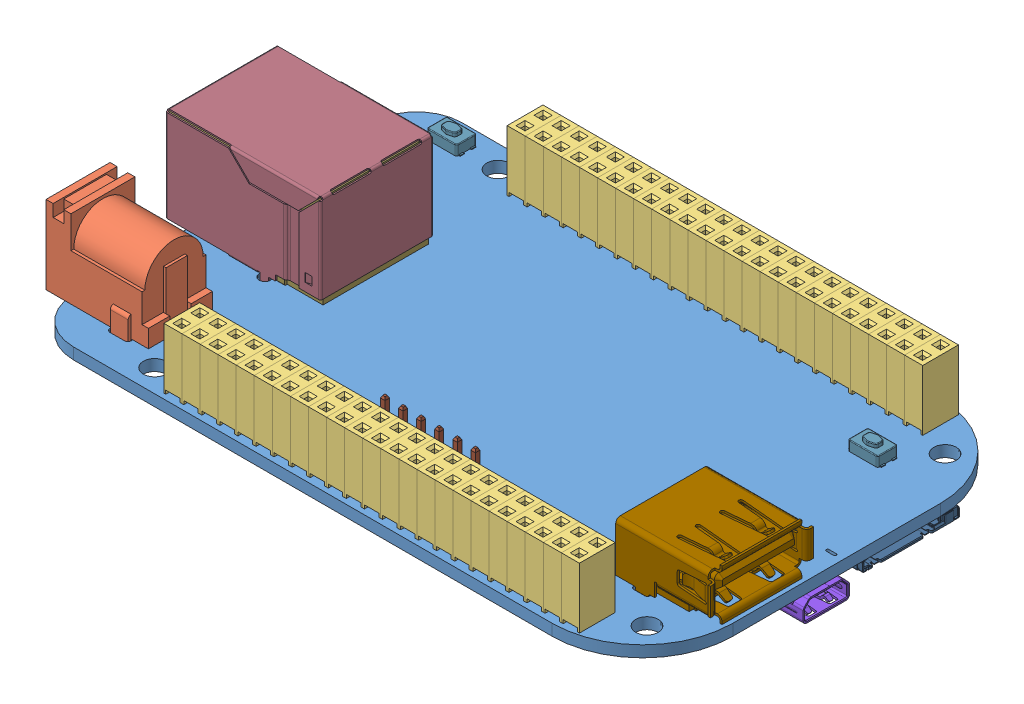
SolidWorks assembly BeagleBone-Black PCBA, configuration Default. Lengths in mm.
Overall size (89.7 19.07 54.61).
157 component instances, 14 part files, 39 mates.
Components (placement in the parent):
- BEAGLEBONE_BLACK Board-1: BEAGLEBONE_BLACK Board [Default] at origin size (86.36 1.59 54.61)
- PG-002A-1: PG-002A [Default] at (-45.704 7.2938 17.779) x (-1 0 0) z (0 0 -1) size (14.4 14.5 9.4)
- SSHS-123-D-02-GT-LF-1: SSHS-123-D-02-GT-LF [Default] at (-23.495 5.1069 25.4) x (0 0 -1) z (1 0 0) size (5.03 11.05 58.42)
  - SSH-1-D-50-1: SSH-1-D-50 [Default] at origin size (5.03 8.51 2.54)
  - C-025-02-T-1: C-025-02-T [Default] at (2.54 -0.3048 0) x (0 0 1) z (1 0 0) size (1.99 9.43 0.41)
  - C-025-02-T-2: C-025-02-T [Default] at (0 -0.3048 0) x (0 0 -1) z (-1 0 0) size (1.99 9.43 0.41)
  - C-025-02-T-3: C-025-02-T [Default] at (2.54 -0.3048 2.54) x (0 0 1) z (1 0 0) size (1.99 9.43 0.41)
  - C-025-02-T-4: C-025-02-T [Default] at (2.54 -0.3048 5.08) x (0 0 1) z (1 0 0) size (1.99 9.43 0.41)
  - C-025-02-T-5: C-025-02-T [Default] at (2.54 -0.3048 7.62) x (0 0 1) z (1 0 0) size (1.99 9.43 0.41)
  - C-025-02-T-6: C-025-02-T [Default] at (2.54 -0.3048 10.16) x (0 0 1) z (1 0 0) size (1.99 9.43 0.41)
  - C-025-02-T-7: C-025-02-T [Default] at (2.54 -0.3048 12.7) x (0 0 1) z (1 0 0) size (1.99 9.43 0.41)
  - C-025-02-T-8: C-025-02-T [Default] at (2.54 -0.3048 15.24) x (0 0 1) z (1 0 0) size (1.99 9.43 0.41)
  - C-025-02-T-9: C-025-02-T [Default] at (2.54 -0.3048 17.78) x (0 0 1) z (1 0 0) size (1.99 9.43 0.41)
  - C-025-02-T-10: C-025-02-T [Default] at (2.54 -0.3048 20.32) x (0 0 1) z (1 0 0) size (1.99 9.43 0.41)
  - C-025-02-T-11: C-025-02-T [Default] at (2.54 -0.3048 22.86) x (0 0 1) z (1 0 0) size (1.99 9.43 0.41)
  - C-025-02-T-12: C-025-02-T [Default] at (2.54 -0.3048 25.4) x (0 0 1) z (1 0 0) size (1.99 9.43 0.41)
  - C-025-02-T-13: C-025-02-T [Default] at (2.54 -0.3048 27.94) x (0 0 1) z (1 0 0) size (1.99 9.43 0.41)
  - C-025-02-T-14: C-025-02-T [Default] at (2.54 -0.3048 30.48) x (0 0 1) z (1 0 0) size (1.99 9.43 0.41)
  - C-025-02-T-15: C-025-02-T [Default] at (2.54 -0.3048 33.02) x (0 0 1) z (1 0 0) size (1.99 9.43 0.41)
  - C-025-02-T-16: C-025-02-T [Default] at (2.54 -0.3048 35.56) x (0 0 1) z (1 0 0) size (1.99 9.43 0.41)
  - C-025-02-T-17: C-025-02-T [Default] at (2.54 -0.3048 38.1) x (0 0 1) z (1 0 0) size (1.99 9.43 0.41)
  - C-025-02-T-18: C-025-02-T [Default] at (2.54 -0.3048 40.64) x (0 0 1) z (1 0 0) size (1.99 9.43 0.41)
  - C-025-02-T-19: C-025-02-T [Default] at (2.54 -0.3048 43.18) x (0 0 1) z (1 0 0) size (1.99 9.43 0.41)
  - C-025-02-T-20: C-025-02-T [Default] at (2.54 -0.3048 45.72) x (0 0 1) z (1 0 0) size (1.99 9.43 0.41)
  - C-025-02-T-21: C-025-02-T [Default] at (2.54 -0.3048 48.26) x (0 0 1) z (1 0 0) size (1.99 9.43 0.41)
  - C-025-02-T-22: C-025-02-T [Default] at (2.54 -0.3048 50.8) x (0 0 1) z (1 0 0) size (1.99 9.43 0.41)
  - C-025-02-T-23: C-025-02-T [Default] at (2.54 -0.3048 53.34) x (0 0 1) z (1 0 0) size (1.99 9.43 0.41)
  - C-025-02-T-24: C-025-02-T [Default] at (2.54 -0.3048 55.88) x (0 0 1) z (1 0 0) size (1.99 9.43 0.41)
  - C-025-02-T-25: C-025-02-T [Default] at (0 -0.3048 2.54) x (0 0 -1) z (-1 0 0) size (1.99 9.43 0.41)
  - C-025-02-T-26: C-025-02-T [Default] at (0 -0.3048 5.08) x (0 0 -1) z (-1 0 0) size (1.99 9.43 0.41)
  - C-025-02-T-27: C-025-02-T [Default] at (0 -0.3048 7.62) x (0 0 -1) z (-1 0 0) size (1.99 9.43 0.41)
  - C-025-02-T-28: C-025-02-T [Default] at (0 -0.3048 10.16) x (0 0 -1) z (-1 0 0) size (1.99 9.43 0.41)
  - C-025-02-T-29: C-025-02-T [Default] at (0 -0.3048 12.7) x (0 0 -1) z (-1 0 0) size (1.99 9.43 0.41)
  - C-025-02-T-30: C-025-02-T [Default] at (0 -0.3048 15.24) x (0 0 -1) z (-1 0 0) size (1.99 9.43 0.41)
  - C-025-02-T-31: C-025-02-T [Default] at (0 -0.3048 17.78) x (0 0 -1) z (-1 0 0) size (1.99 9.43 0.41)
  - C-025-02-T-32: C-025-02-T [Default] at (0 -0.3048 20.32) x (0 0 -1) z (-1 0 0) size (1.99 9.43 0.41)
  - C-025-02-T-33: C-025-02-T [Default] at (0 -0.3048 22.86) x (0 0 -1) z (-1 0 0) size (1.99 9.43 0.41)
  - C-025-02-T-34: C-025-02-T [Default] at (0 -0.3048 25.4) x (0 0 -1) z (-1 0 0) size (1.99 9.43 0.41)
  - C-025-02-T-35: C-025-02-T [Default] at (0 -0.3048 27.94) x (0 0 -1) z (-1 0 0) size (1.99 9.43 0.41)
  - C-025-02-T-36: C-025-02-T [Default] at (0 -0.3048 30.48) x (0 0 -1) z (-1 0 0) size (1.99 9.43 0.41)
  - C-025-02-T-37: C-025-02-T [Default] at (0 -0.3048 33.02) x (0 0 -1) z (-1 0 0) size (1.99 9.43 0.41)
  - C-025-02-T-38: C-025-02-T [Default] at (0 -0.3048 35.56) x (0 0 -1) z (-1 0 0) size (1.99 9.43 0.41)
  - C-025-02-T-39: C-025-02-T [Default] at (0 -0.3048 38.1) x (0 0 -1) z (-1 0 0) size (1.99 9.43 0.41)
  - C-025-02-T-40: C-025-02-T [Default] at (0 -0.3048 40.64) x (0 0 -1) z (-1 0 0) size (1.99 9.43 0.41)
  - C-025-02-T-41: C-025-02-T [Default] at (0 -0.3048 43.18) x (0 0 -1) z (-1 0 0) size (1.99 9.43 0.41)
  - C-025-02-T-42: C-025-02-T [Default] at (0 -0.3048 45.72) x (0 0 -1) z (-1 0 0) size (1.99 9.43 0.41)
  - C-025-02-T-43: C-025-02-T [Default] at (0 -0.3048 48.26) x (0 0 -1) z (-1 0 0) size (1.99 9.43 0.41)
  - C-025-02-T-44: C-025-02-T [Default] at (0 -0.3048 50.8) x (0 0 -1) z (-1 0 0) size (1.99 9.43 0.41)
  - C-025-02-T-45: C-025-02-T [Default] at (0 -0.3048 53.34) x (0 0 -1) z (-1 0 0) size (1.99 9.43 0.41)
  - C-025-02-T-46: C-025-02-T [Default] at (0 -0.3048 55.88) x (0 0 -1) z (-1 0 0) size (1.99 9.43 0.41)
  - SSH-1-D-50-2: SSH-1-D-50 [Default] at (0 0 2.54) size (5.03 8.51 2.54)
  - SSH-1-D-50-3: SSH-1-D-50 [Default] at (0 0 5.08) size (5.03 8.51 2.54)
  - SSH-1-D-50-4: SSH-1-D-50 [Default] at (0 0 7.62) size (5.03 8.51 2.54)
  - SSH-1-D-50-5: SSH-1-D-50 [Default] at (0 0 10.16) size (5.03 8.51 2.54)
  - SSH-1-D-50-6: SSH-1-D-50 [Default] at (0 0 12.7) size (5.03 8.51 2.54)
  - SSH-1-D-50-7: SSH-1-D-50 [Default] at (0 0 15.24) size (5.03 8.51 2.54)
  - SSH-1-D-50-8: SSH-1-D-50 [Default] at (0 0 17.78) size (5.03 8.51 2.54)
  - SSH-1-D-50-9: SSH-1-D-50 [Default] at (0 0 20.32) size (5.03 8.51 2.54)
  - SSH-1-D-50-10: SSH-1-D-50 [Default] at (0 0 22.86) size (5.03 8.51 2.54)
  - SSH-1-D-50-11: SSH-1-D-50 [Default] at (0 0 25.4) size (5.03 8.51 2.54)
  - SSH-1-D-50-12: SSH-1-D-50 [Default] at (0 0 27.94) size (5.03 8.51 2.54)
  - SSH-1-D-50-13: SSH-1-D-50 [Default] at (0 0 30.48) size (5.03 8.51 2.54)
  - SSH-1-D-50-14: SSH-1-D-50 [Default] at (0 0 33.02) size (5.03 8.51 2.54)
  - SSH-1-D-50-15: SSH-1-D-50 [Default] at (0 0 35.56) size (5.03 8.51 2.54)
  - SSH-1-D-50-16: SSH-1-D-50 [Default] at (0 0 38.1) size (5.03 8.51 2.54)
  - SSH-1-D-50-17: SSH-1-D-50 [Default] at (0 0 40.64) size (5.03 8.51 2.54)
  - SSH-1-D-50-18: SSH-1-D-50 [Default] at (0 0 43.18) size (5.03 8.51 2.54)
  - SSH-1-D-50-19: SSH-1-D-50 [Default] at (0 0 45.72) size (5.03 8.51 2.54)
  - SSH-1-D-50-20: SSH-1-D-50 [Default] at (0 0 48.26) size (5.03 8.51 2.54)
  - SSH-1-D-50-21: SSH-1-D-50 [Default] at (0 0 50.8) size (5.03 8.51 2.54)
  - SSH-1-D-50-22: SSH-1-D-50 [Default] at (0 0 53.34) size (5.03 8.51 2.54)
  - SSH-1-D-50-23: SSH-1-D-50 [Default] at (0 0 55.88) size (5.03 8.51 2.54)
- SSHS-123-D-02-GT-LF-2: SSHS-123-D-02-GT-LF [Default] at (-23.495 5.0482 -22.86) x (0 0 -1) z (1 0 0) size (5.03 11.05 58.42)
  - SSH-1-D-50-1: SSH-1-D-50 [Default] at origin size (5.03 8.51 2.54)
  - C-025-02-T-1: C-025-02-T [Default] at (2.54 -0.3048 0) x (0 0 1) z (1 0 0) size (1.99 9.43 0.41)
  - C-025-02-T-2: C-025-02-T [Default] at (0 -0.3048 0) x (0 0 -1) z (-1 0 0) size (1.99 9.43 0.41)
  - C-025-02-T-3: C-025-02-T [Default] at (2.54 -0.3048 2.54) x (0 0 1) z (1 0 0) size (1.99 9.43 0.41)
  - C-025-02-T-4: C-025-02-T [Default] at (2.54 -0.3048 5.08) x (0 0 1) z (1 0 0) size (1.99 9.43 0.41)
  - C-025-02-T-5: C-025-02-T [Default] at (2.54 -0.3048 7.62) x (0 0 1) z (1 0 0) size (1.99 9.43 0.41)
  - C-025-02-T-6: C-025-02-T [Default] at (2.54 -0.3048 10.16) x (0 0 1) z (1 0 0) size (1.99 9.43 0.41)
  - C-025-02-T-7: C-025-02-T [Default] at (2.54 -0.3048 12.7) x (0 0 1) z (1 0 0) size (1.99 9.43 0.41)
  - C-025-02-T-8: C-025-02-T [Default] at (2.54 -0.3048 15.24) x (0 0 1) z (1 0 0) size (1.99 9.43 0.41)
  - C-025-02-T-9: C-025-02-T [Default] at (2.54 -0.3048 17.78) x (0 0 1) z (1 0 0) size (1.99 9.43 0.41)
  - C-025-02-T-10: C-025-02-T [Default] at (2.54 -0.3048 20.32) x (0 0 1) z (1 0 0) size (1.99 9.43 0.41)
  - C-025-02-T-11: C-025-02-T [Default] at (2.54 -0.3048 22.86) x (0 0 1) z (1 0 0) size (1.99 9.43 0.41)
  - C-025-02-T-12: C-025-02-T [Default] at (2.54 -0.3048 25.4) x (0 0 1) z (1 0 0) size (1.99 9.43 0.41)
  - C-025-02-T-13: C-025-02-T [Default] at (2.54 -0.3048 27.94) x (0 0 1) z (1 0 0) size (1.99 9.43 0.41)
  - C-025-02-T-14: C-025-02-T [Default] at (2.54 -0.3048 30.48) x (0 0 1) z (1 0 0) size (1.99 9.43 0.41)
  - C-025-02-T-15: C-025-02-T [Default] at (2.54 -0.3048 33.02) x (0 0 1) z (1 0 0) size (1.99 9.43 0.41)
  - C-025-02-T-16: C-025-02-T [Default] at (2.54 -0.3048 35.56) x (0 0 1) z (1 0 0) size (1.99 9.43 0.41)
  - C-025-02-T-17: C-025-02-T [Default] at (2.54 -0.3048 38.1) x (0 0 1) z (1 0 0) size (1.99 9.43 0.41)
  - C-025-02-T-18: C-025-02-T [Default] at (2.54 -0.3048 40.64) x (0 0 1) z (1 0 0) size (1.99 9.43 0.41)
  - C-025-02-T-19: C-025-02-T [Default] at (2.54 -0.3048 43.18) x (0 0 1) z (1 0 0) size (1.99 9.43 0.41)
  - C-025-02-T-20: C-025-02-T [Default] at (2.54 -0.3048 45.72) x (0 0 1) z (1 0 0) size (1.99 9.43 0.41)
  - C-025-02-T-21: C-025-02-T [Default] at (2.54 -0.3048 48.26) x (0 0 1) z (1 0 0) size (1.99 9.43 0.41)
  - C-025-02-T-22: C-025-02-T [Default] at (2.54 -0.3048 50.8) x (0 0 1) z (1 0 0) size (1.99 9.43 0.41)
  - C-025-02-T-23: C-025-02-T [Default] at (2.54 -0.3048 53.34) x (0 0 1) z (1 0 0) size (1.99 9.43 0.41)
  - C-025-02-T-24: C-025-02-T [Default] at (2.54 -0.3048 55.88) x (0 0 1) z (1 0 0) size (1.99 9.43 0.41)
  - C-025-02-T-25: C-025-02-T [Default] at (0 -0.3048 2.54) x (0 0 -1) z (-1 0 0) size (1.99 9.43 0.41)
  - C-025-02-T-26: C-025-02-T [Default] at (0 -0.3048 5.08) x (0 0 -1) z (-1 0 0) size (1.99 9.43 0.41)
  - C-025-02-T-27: C-025-02-T [Default] at (0 -0.3048 7.62) x (0 0 -1) z (-1 0 0) size (1.99 9.43 0.41)
  - C-025-02-T-28: C-025-02-T [Default] at (0 -0.3048 10.16) x (0 0 -1) z (-1 0 0) size (1.99 9.43 0.41)
  - C-025-02-T-29: C-025-02-T [Default] at (0 -0.3048 12.7) x (0 0 -1) z (-1 0 0) size (1.99 9.43 0.41)
  - C-025-02-T-30: C-025-02-T [Default] at (0 -0.3048 15.24) x (0 0 -1) z (-1 0 0) size (1.99 9.43 0.41)
  - C-025-02-T-31: C-025-02-T [Default] at (0 -0.3048 17.78) x (0 0 -1) z (-1 0 0) size (1.99 9.43 0.41)
  - C-025-02-T-32: C-025-02-T [Default] at (0 -0.3048 20.32) x (0 0 -1) z (-1 0 0) size (1.99 9.43 0.41)
  - C-025-02-T-33: C-025-02-T [Default] at (0 -0.3048 22.86) x (0 0 -1) z (-1 0 0) size (1.99 9.43 0.41)
  - C-025-02-T-34: C-025-02-T [Default] at (0 -0.3048 25.4) x (0 0 -1) z (-1 0 0) size (1.99 9.43 0.41)
  - C-025-02-T-35: C-025-02-T [Default] at (0 -0.3048 27.94) x (0 0 -1) z (-1 0 0) size (1.99 9.43 0.41)
  - C-025-02-T-36: C-025-02-T [Default] at (0 -0.3048 30.48) x (0 0 -1) z (-1 0 0) size (1.99 9.43 0.41)
  - C-025-02-T-37: C-025-02-T [Default] at (0 -0.3048 33.02) x (0 0 -1) z (-1 0 0) size (1.99 9.43 0.41)
  - C-025-02-T-38: C-025-02-T [Default] at (0 -0.3048 35.56) x (0 0 -1) z (-1 0 0) size (1.99 9.43 0.41)
  - C-025-02-T-39: C-025-02-T [Default] at (0 -0.3048 38.1) x (0 0 -1) z (-1 0 0) size (1.99 9.43 0.41)
  - C-025-02-T-40: C-025-02-T [Default] at (0 -0.3048 40.64) x (0 0 -1) z (-1 0 0) size (1.99 9.43 0.41)
  - C-025-02-T-41: C-025-02-T [Default] at (0 -0.3048 43.18) x (0 0 -1) z (-1 0 0) size (1.99 9.43 0.41)
  - C-025-02-T-42: C-025-02-T [Default] at (0 -0.3048 45.72) x (0 0 -1) z (-1 0 0) size (1.99 9.43 0.41)
  - C-025-02-T-43: C-025-02-T [Default] at (0 -0.3048 48.26) x (0 0 -1) z (-1 0 0) size (1.99 9.43 0.41)
  - C-025-02-T-44: C-025-02-T [Default] at (0 -0.3048 50.8) x (0 0 -1) z (-1 0 0) size (1.99 9.43 0.41)
  - C-025-02-T-45: C-025-02-T [Default] at (0 -0.3048 53.34) x (0 0 -1) z (-1 0 0) size (1.99 9.43 0.41)
  - C-025-02-T-46: C-025-02-T [Default] at (0 -0.3048 55.88) x (0 0 -1) z (-1 0 0) size (1.99 9.43 0.41)
  - SSH-1-D-50-2: SSH-1-D-50 [Default] at (0 0 2.54) size (5.03 8.51 2.54)
  - SSH-1-D-50-3: SSH-1-D-50 [Default] at (0 0 5.08) size (5.03 8.51 2.54)
  - SSH-1-D-50-4: SSH-1-D-50 [Default] at (0 0 7.62) size (5.03 8.51 2.54)
  - SSH-1-D-50-5: SSH-1-D-50 [Default] at (0 0 10.16) size (5.03 8.51 2.54)
  - SSH-1-D-50-6: SSH-1-D-50 [Default] at (0 0 12.7) size (5.03 8.51 2.54)
  - SSH-1-D-50-7: SSH-1-D-50 [Default] at (0 0 15.24) size (5.03 8.51 2.54)
  - SSH-1-D-50-8: SSH-1-D-50 [Default] at (0 0 17.78) size (5.03 8.51 2.54)
  - SSH-1-D-50-9: SSH-1-D-50 [Default] at (0 0 20.32) size (5.03 8.51 2.54)
  - SSH-1-D-50-10: SSH-1-D-50 [Default] at (0 0 22.86) size (5.03 8.51 2.54)
  - SSH-1-D-50-11: SSH-1-D-50 [Default] at (0 0 25.4) size (5.03 8.51 2.54)
  - SSH-1-D-50-12: SSH-1-D-50 [Default] at (0 0 27.94) size (5.03 8.51 2.54)
  - SSH-1-D-50-13: SSH-1-D-50 [Default] at (0 0 30.48) size (5.03 8.51 2.54)
  - SSH-1-D-50-14: SSH-1-D-50 [Default] at (0 0 33.02) size (5.03 8.51 2.54)
  - SSH-1-D-50-15: SSH-1-D-50 [Default] at (0 0 35.56) size (5.03 8.51 2.54)
  - SSH-1-D-50-16: SSH-1-D-50 [Default] at (0 0 38.1) size (5.03 8.51 2.54)
  - SSH-1-D-50-17: SSH-1-D-50 [Default] at (0 0 40.64) size (5.03 8.51 2.54)
  - SSH-1-D-50-18: SSH-1-D-50 [Default] at (0 0 43.18) size (5.03 8.51 2.54)
  - SSH-1-D-50-19: SSH-1-D-50 [Default] at (0 0 45.72) size (5.03 8.51 2.54)
  - SSH-1-D-50-20: SSH-1-D-50 [Default] at (0 0 48.26) size (5.03 8.51 2.54)
  - SSH-1-D-50-21: SSH-1-D-50 [Default] at (0 0 50.8) size (5.03 8.51 2.54)
  - SSH-1-D-50-22: SSH-1-D-50 [Default] at (0 0 53.34) size (5.03 8.51 2.54)
  - SSH-1-D-50-23: SSH-1-D-50 [Default] at (0 0 55.88) size (5.03 8.51 2.54)
- UX60SC-MB-5ST-1: UX60SC-MB-5ST [Default] at (-63.0947 -3.2937 -14.5842) x (0 0 -1) z (0 -1 0) size (9.81 7.01 3.99)
  - UX60SC-MB-5ST-1: UX60SC-MB-5ST [Default] at (2.4471 21.2893 1.05) x (-1 0 0) z (0 0 1) size (9.81 7.01 3.99)
- 10118241-001rlf_asm-1: 10118241-001rlf_asm [Default] at (43.88 -3.6937 2.1589) x (0 0 1) z (1 0 0) size (8.91 3.53 7.5)
  - MSBR-1-1: MSBR-1 [Default] at origin size (5.9 2.78 6.03)
  - MSBR-2-1: MSBR-2 [Default] at origin size (5.5 0.08 3.5)
  - _HDMI_D_TYPE_RECEPTACLE-1: _HDMI_D_TYPE_RECEPTACLE [Default] at origin size (8.91 3.45 7.5)
- 87520-0010BLF-1: 87520-0010BLF [Default] at (29.1502 4.3468 10.4878) x (0 0 -1) z (1 0 0) size (14.5 10.48 14)
- SCHA5B0200-1: SCHA5B0200 [Default] at (28.23 -0.7937 -10.405) x (0 0 1) z (0 -1 0) size (15.01 15.51 1.52)
- i68000-x06-1: i68000-x06 [Default] at (-0.635 0.9969 19.685) size (15.24 10.79 2.41)
- LPJ0011BBNL - RJ45-1: LPJ0011BBNL - RJ45 [Default] at (-34.895 7.5438 -2.535) x (0 0 1) z (-1 0 0) size (15.88 16.55 21.84)
  - LINK LP0011BBNL Internal-1: LINK LP0011BBNL Internal [Default] x (-1 0 0) z (0 0 1) size (15.48 16.35 21.44)
  - LINK LP0011BBNL-1: LINK LP0011BBNL [Default] at (0 0 0.03) x (-1 0 0) z (0 -1 0) size (15.88 21.84 16.25)
- KMR231GLFS-1: KMR231GLFS [Default] at (32.3628 1.4938 -15.8975) size (4.6 1.9 2.8)
- KMR231GLFS-2: KMR231GLFS [Default] at (-35.1378 1.4938 -14.5984) size (4.6 1.9 2.8)
- KMR231GLFS-3: KMR231GLFS [Default] at (-35.1378 1.4938 -24.1858) size (4.6 1.9 2.8)
Mates (geometry in assembly coordinates):
- Coincident10: coincident: plane of SSHS-123-D-02-GT-LF-1/SSH-1-D-50-23 through (33.655 0.8524 26.6446) normal (1 0 0); plane of SSHS-123-D-02-GT-LF-2/SSH-1-D-50-23 through (33.655 0.7937 -21.6154) normal (1 0 0)
- Coincident14: coincident: plane of BEAGLEBONE_BLACK Board-1 through (0 0.7937 0) normal (0 1 0); plane of 87520-0010BLF-1 through (29.1502 0.7937 10.4878) normal (0 -1 0)
- Width2: width: plane of 87520-0010BLF-1 through (30.0077 -1.9983 13.7878) normal (-1 0 0); plane of 87520-0010BLF-1 through (30.3127 -1.9983 14.1878) normal (1 0 0); cylinder of BEAGLEBONE_BLACK Board-1 through (30.1602 0.7937 13.9878) axis (0 -1 0) radius 0.46
- Width3: width: plane of 87520-0010BLF-1 through (30.0077 -1.9983 14.1878) normal (0 0 1); plane of 87520-0010BLF-1 through (30.3127 -1.9983 13.7878) normal (0 0 -1); cylinder of BEAGLEBONE_BLACK Board-1 through (30.1602 0.7937 13.9878) axis (0 -1 0) radius 0.46
- Parallel1: parallel: plane of BEAGLEBONE_BLACK Board-1 through (43.18 0.7937 -27.305) normal (1 0 0); plane of 87520-0010BLF-1 through (29.1502 4.3468 10.4878) normal (-1 0 0)
- Width4: width: plane of i68000-x06-1 through (-0.9525 9.1758 20.0025) normal (-1 0 0); plane of i68000-x06-1 through (-0.3175 9.1758 19.3675) normal (1 0 0); cylinder of BEAGLEBONE_BLACK Board-1 through (-0.635 0.7937 19.685) axis (0 -1 0) radius 0.508
- Parallel2: parallel: plane of BEAGLEBONE_BLACK Board-1 through (-43.18 0.7937 27.305) normal (0 0 1); plane of i68000-x06-1 through (-1.905 0.9969 20.8915) normal (0 0 1)
- Coincident15: coincident: plane of BEAGLEBONE_BLACK Board-1 through (0 0.7937 0) normal (0 1 0); plane of i68000-x06-1 through (10.1854 0.7937 20.2438) normal (0 -1 0)
- Width6: width: plane of i68000-x06-1 through (12.3825 9.1758 20.0025) normal (0 0 1); plane of i68000-x06-1 through (11.7475 9.1758 19.3675) normal (0 0 -1); cylinder of BEAGLEBONE_BLACK Board-1 through (12.065 0.7937 19.685) axis (0 -1 0) radius 0.508
- Width7: width: plane of PG-002A-1 through (-31.824 11.7938 22.279) normal (1 0 0); plane of PG-002A-1 through (-32.184 -1.2063 17.779) normal (-1 0 0); plane of BEAGLEBONE_BLACK Board-1 through (-31.5036 0.7937 19.03) normal (-1 0 0); plane of BEAGLEBONE_BLACK Board-1 through (-32.5044 0.7937 19.03) normal (1 0 0)
- Width8: width: plane of PG-002A-1 through (-33.754 -2.7062 22.679) normal (0 0 1); plane of PG-002A-1 through (-33.754 -2.7062 22.279) normal (0 0 -1); plane of BEAGLEBONE_BLACK Board-1 through (-36.0012 0.7937 22.9794) normal (0 0 -1); plane of BEAGLEBONE_BLACK Board-1 through (-36.0012 0.7937 21.9786) normal (0 0 1)
- Coincident18: coincident: plane of BEAGLEBONE_BLACK Board-1 through (0 -0.7937 0) normal (0 -1 0); plane of UX60SC-MB-5ST-1/UX60SC-MB-5ST-1 through (-41.0261 -0.7937 -12.005) normal (0 1 0)
- Distance1: distance = 0.6461 mm: plane of UX60SC-MB-5ST-1/UX60SC-MB-5ST-1 through (-43.8261 -0.2847 -19.9333) normal (-1 0 0); plane of BEAGLEBONE_BLACK Board-1 through (-43.18 0.7937 -27.305) normal (-1 0 0)
- Distance2: distance = 5.5 mm: plane of UX60SC-MB-5ST-1/UX60SC-MB-5ST-1 through (-39.2261 -1.1937 -21.805) normal (0 0 -1); plane of BEAGLEBONE_BLACK Board-1 through (-43.18 0.7937 -27.305) normal (0 0 -1)
- Coincident22: coincident: plane of BEAGLEBONE_BLACK Board-1 through (0 -0.7937 0) normal (0 -1 0); plane of SCHA5B0200-1 through (42.39 -0.7937 -17.9049) normal (0 1 0)
- Parallel3: parallel: plane of BEAGLEBONE_BLACK Board-1 through (-43.18 0.7937 -27.305) normal (0 0 -1); plane of SCHA5B0200-1 through (34.92 -0.8463 -17.355) normal (0 0 -1)
- Distance3: distance = 9.4 mm: plane of BEAGLEBONE_BLACK Board-1 through (-43.18 0.7937 -27.305) normal (0 0 -1); plane of SCHA5B0200-1 through (30.4197 -0.7937 -17.905) normal (0 0 -1)
- Distance4: distance = 0.05 mm: plane of BEAGLEBONE_BLACK Board-1 through (43.18 0.7937 -27.305) normal (1 0 0); plane of SCHA5B0200-1 through (43.23 -2.2037 -13.4675) normal (1 0 0)
- Coincident25: coincident: plane of 10118241-001rlf_asm-1/_HDMI_D_TYPE_RECEPTACLE-1 through (43.9764 -0.7937 2.6555) normal (0 1 0); plane of BEAGLEBONE_BLACK Board-1 through (0 -0.7937 0) normal (0 -1 0)
- Parallel4: parallel: plane of BEAGLEBONE_BLACK Board-1 through (43.18 0.7937 -27.305) normal (1 0 0); plane of 10118241-001rlf_asm-1/_HDMI_D_TYPE_RECEPTACLE-1 through (43.88 -3.4792 -0.7011) normal (1 0 0)
- Width9: width: plane of 10118241-001rlf_asm-1/_HDMI_D_TYPE_RECEPTACLE-1 through (36.23 -3.249 -1.0911) normal (0 0 -1); plane of 10118241-001rlf_asm-1/_HDMI_D_TYPE_RECEPTACLE-1 through (36.334 -3.249 -0.7911) normal (0 0 1); plane of BEAGLEBONE_BLACK Board-1 through (40.9621 0.7937 -1.1395) normal (0 0 1); plane of BEAGLEBONE_BLACK Board-1 through (40.9621 0.7937 -0.7426) normal (0 0 -1)
- Distance5: distance = 0.7 mm: plane of BEAGLEBONE_BLACK Board-1 through (43.18 0.7937 -27.305) normal (1 0 0); plane of 10118241-001rlf_asm-1/_HDMI_D_TYPE_RECEPTACLE-1 through (43.88 -3.4792 -0.7011) normal (1 0 0)
- Parallel5: parallel: plane of BEAGLEBONE_BLACK Board-1 through (-43.18 0.7937 -27.305) normal (0 0 -1); plane of SSHS-123-D-02-GT-LF-2/SSH-1-D-50-18 through (18.415 0.7937 -26.6446) normal (0 0 -1)
- Coincident27: coincident: plane of BEAGLEBONE_BLACK Board-1 through (0 0.7937 0) normal (0 1 0); plane of SSHS-123-D-02-GT-LF-2/SSH-1-D-50-20 through (25.781 0.7937 -21.6154) normal (0 -1 0)
- Width10: width: plane of SSHS-123-D-02-GT-LF-2/C-025-02-T-24 through (33.3913 7.744 -25.1968) normal (0 0 1); plane of SSHS-123-D-02-GT-LF-2/C-025-02-T-24 through (33.3913 7.744 -25.6032) normal (0 0 -1); cylinder of BEAGLEBONE_BLACK Board-1 through (32.385 0.7937 -25.4) axis (0 -1 0) radius 0.51
- Width11: width: plane of SSHS-123-D-02-GT-LF-2/C-025-02-T-24 through (32.7787 -1.4414 -25.1968) normal (1 0 0); plane of SSHS-123-D-02-GT-LF-2/C-025-02-T-24 through (31.9913 1.3017 -25.1968) normal (-1 0 0); cylinder of BEAGLEBONE_BLACK Board-1 through (32.385 0.7937 -25.4) axis (0 -1 0) radius 0.51
- Width12: width: plane of SSHS-123-D-02-GT-LF-1/C-025-02-T-46 through (31.3787 7.8026 25.6032) normal (0 0 1); plane of SSHS-123-D-02-GT-LF-1/C-025-02-T-46 through (31.3787 7.8026 25.1968) normal (0 0 -1); cylinder of BEAGLEBONE_BLACK Board-1 through (32.385 0.7937 25.4) axis (0 -1 0) radius 0.51
- Concentric1: concentric: cylinder of BEAGLEBONE_BLACK Board-1 through (-34.925 0.7937 3.175) axis (0 -1 0) radius 1.6256; cylinder of LPJ0011BBNL - RJ45-1/LINK LP0011BBNL Internal-1 through (-34.925 -2.2563 3.175) axis (0 1 0) radius 1.6
- Coincident28: coincident: plane of BEAGLEBONE_BLACK Board-1 through (0 0.7937 0) normal (0 1 0); plane of LPJ0011BBNL - RJ45-1/LINK LP0011BBNL-1 through (-32.925 0.7937 -10.3054) normal (0 -1 0)
- Parallel7: parallel: plane of BEAGLEBONE_BLACK Board-1 through (-43.18 0.7937 -27.305) normal (-1 0 0); plane of LPJ0011BBNL - RJ45-1/LINK LP0011BBNL-1 through (-45.815 0.7937 5.105) normal (-1 0 0)
- Coincident30: coincident: plane of BEAGLEBONE_BLACK Board-1 through (0 0.7937 0) normal (0 1 0); plane of KMR231GLFS-3 through (-35.1378 0.7937 -24.1858) normal (0 -1 0)
- Coincident31: coincident: plane of BEAGLEBONE_BLACK Board-1 through (0 0.7937 0) normal (0 1 0); plane of KMR231GLFS-2 through (-35.1378 0.7937 -14.5984) normal (0 -1 0)
- Coincident32: coincident: plane of BEAGLEBONE_BLACK Board-1 through (0 0.7937 0) normal (0 1 0); plane of KMR231GLFS-1 through (32.3628 0.7937 -15.8975) normal (0 -1 0)
- Distance6: distance = 8.7172 mm: plane of BEAGLEBONE_BLACK Board-1 through (43.18 0.7937 -27.305) normal (1 0 0); plane of KMR231GLFS-1 through (34.4628 2.1938 -17.2975) normal (1 0 0)
- Distance7: distance = 10.0075 mm: plane of BEAGLEBONE_BLACK Board-1 through (-43.18 0.7937 -27.305) normal (0 0 -1); plane of KMR231GLFS-1 through (30.2628 2.1938 -17.2975) normal (0 0 -1)
- Distance8: distance = 1.7192 mm: plane of BEAGLEBONE_BLACK Board-1 through (-43.18 0.7937 -27.305) normal (0 0 -1); plane of KMR231GLFS-3 through (-37.2378 2.1938 -25.5858) normal (0 0 -1)
- Distance9: distance = 5.9422 mm: plane of BEAGLEBONE_BLACK Board-1 through (-43.18 0.7937 -27.305) normal (-1 0 0); plane of KMR231GLFS-3 through (-37.2378 2.1938 -25.5858) normal (-1 0 0)
- Coincident37: coincident: plane of KMR231GLFS-2 through (-37.2378 2.1938 -15.9984) normal (-1 0 0); plane of KMR231GLFS-3 through (-37.2378 2.1938 -25.5858) normal (-1 0 0)
- Distance10: distance = 11.3066 mm: plane of KMR231GLFS-2 through (-37.2378 2.1938 -15.9984) normal (0 0 -1); plane of BEAGLEBONE_BLACK Board-1 through (-43.18 0.7937 -27.305) normal (0 0 -1)
